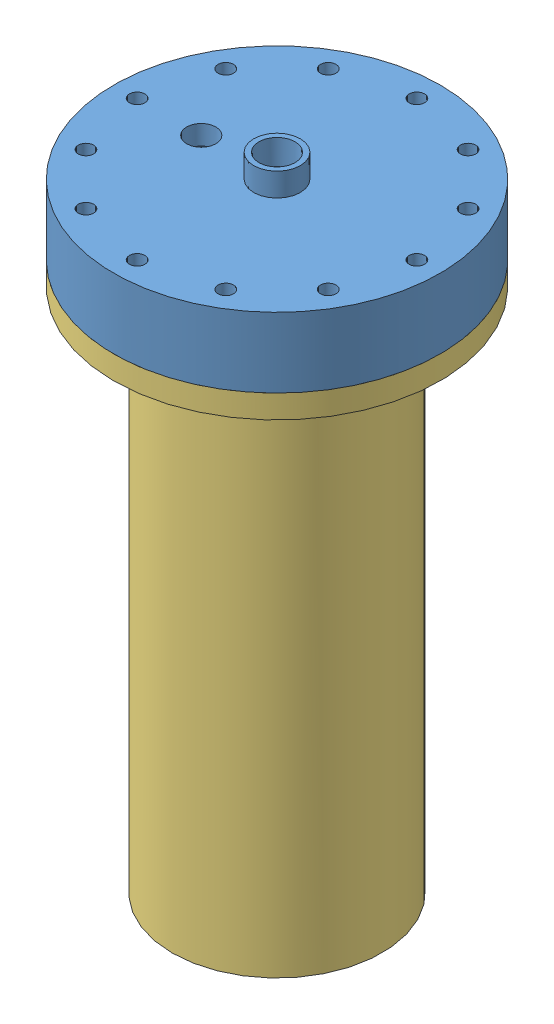
SolidWorks assembly APL1_firstEngineTest, configuration Default. Lengths in mm.
Overall size (177.8 349.25 177.8).
6 component instances, 6 part files, 12 mates.
Components (placement in the parent):
- APL1_dome-1: APL1_dome [Default] at origin size (177.8 50.8 177.8)
- APL1_TopInjectorPlate-1: APL1_TopInjectorPlate [Default] at (0 12.7 0) x (-0.647207 0 0.762314) z (-0.762314 0 -0.647207) size (63.5 6.35 63.5)
- APL1_OuterChamberCasing-1: APL1_OuterChamberCasing [Default] at origin size (177.8 298.45 177.8)
- APL1_LowerInjectorPlate-1: APL1_LowerInjectorPlate [Default] at (0 -6.35 0) size (114.3 19.05 114.3)
- APL1_ablativeInsert-1: APL1_ablativeInsert [Default] at (0 -6.35 0) x (0.99452 0 -0.104543) z (0.104543 0 0.99452) size (102.26 152.4 102.26)
- APL1_graphiteInsert-1: APL1_graphiteInsert [Default] at (0 -158.75 0) size (102.26 131.11 102.26)
Mates (geometry in assembly coordinates):
- Coincident1: coordinate: point of APL1_dome-1
- Concentric1: concentric aligned: cylinder of APL1_dome-1 through (0 0 0) axis (0 -1 0) radius 88.9; cylinder of APL1_TopInjectorPlate-1 through (0 12.7 0) axis (0 -1 0) radius 31.75
- Concentric2: concentric anti-aligned: cylinder of APL1_dome-1 through (0 0 0) axis (0 -1 0) radius 88.9; cylinder of APL1_OuterChamberCasing-1 through (0 0 0) axis (0 1 0) radius 88.9
- Coincident3: coincident anti-aligned: plane of APL1_dome-1 through (-25.4 19.05 0) normal (0 -1 0); plane of APL1_TopInjectorPlate-1 through (0 19.05 0) normal (0 1 0)
- Coincident4: coincident anti-aligned: plane of APL1_dome-1 through (-55.9435 0 0) normal (0 -1 0); plane of APL1_OuterChamberCasing-1 through (-57.15 0 0) normal (0 1 0)
- Concentric3: concentric anti-aligned: cylinder of APL1_dome-1 through (0 0 0) axis (0 -1 0) radius 88.9; cylinder of APL1_LowerInjectorPlate-1 through (0 0 0) axis (0 1 0) radius 57.15
- Coincident5: coincident anti-aligned: plane of APL1_OuterChamberCasing-1 through (-51.1302 -6.35 0) normal (0 1 0); plane of APL1_LowerInjectorPlate-1 through (0 -6.35 0) normal (0 -1 0)
- Concentric4: concentric aligned: cylinder of APL1_dome-1 through (76.2 38.1 0) axis (0 1 0) radius 4.2164; cylinder of APL1_OuterChamberCasing-1 through (76.2 0 0) axis (0 1 0) radius 4.2164
- Concentric5: concentric aligned: cylinder of APL1_OuterChamberCasing-1 through (0 0 0) axis (0 1 0) radius 51.1302; cylinder of APL1_ablativeInsert-1 through (0 -6.35 0) axis (0 1 0) radius 51.1302
- Coincident6: coincident anti-aligned: plane of APL1_LowerInjectorPlate-1 through (0 -6.35 0) normal (0 -1 0); plane of APL1_ablativeInsert-1 through (-37.8912 -6.35 3.9831) normal (0 1 0)
- Concentric6: concentric aligned: cylinder of APL1_OuterChamberCasing-1 through (0 0 0) axis (0 1 0) radius 51.1302; cylinder of APL1_graphiteInsert-1 through (0 -158.75 0) axis (0 1 0) radius 51.1302
- Coincident7: coincident anti-aligned: plane of APL1_ablativeInsert-1 through (-37.8912 -158.75 3.9831) normal (0 -1 0); plane of APL1_graphiteInsert-1 through (-44.7802 -158.75 0) normal (0 1 0)
